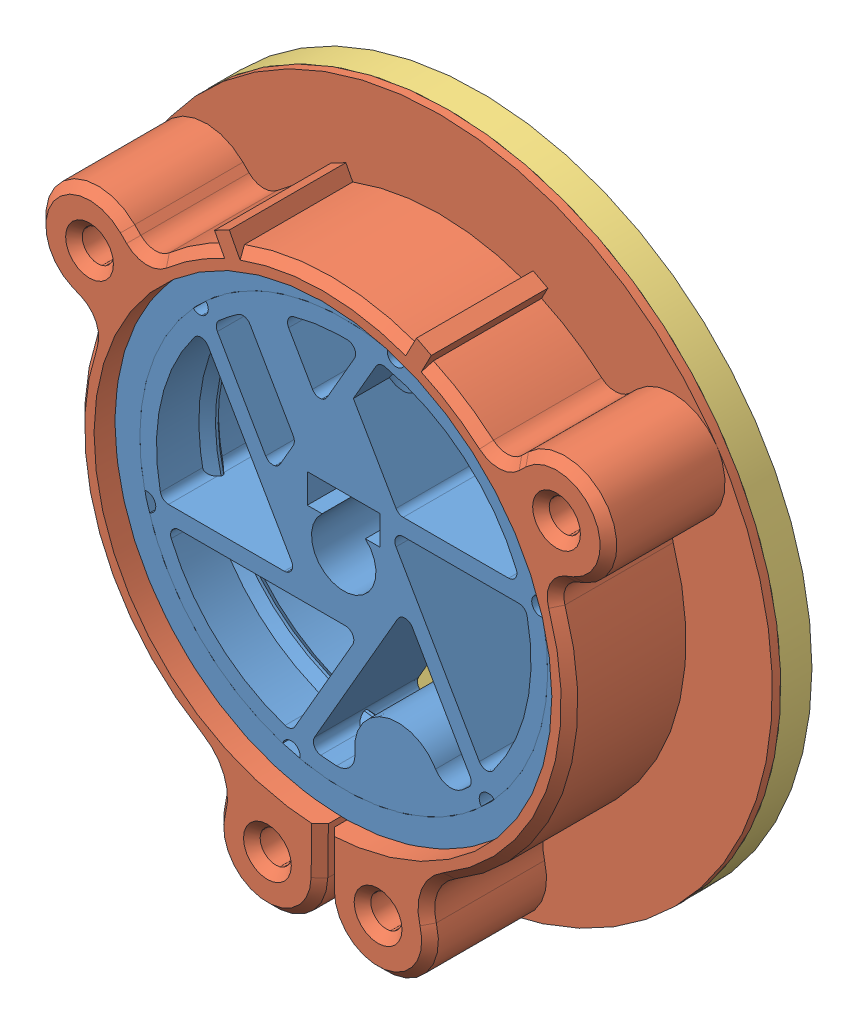
SolidWorks assembly wheel-mold, configuration Default. Lengths in mm.
Overall size (64 64 15).
3 component instances, 3 part files, 3 mates.
Components (placement in the parent):
- drive-wheel-hub-1: drive-wheel-hub [Default] at origin size (44 44 10)
- mold-rim^wheel-mold-1: mold-rim^wheel-mold [Default] at origin size (64 63.47 12.02) (virtual)
- mold-base^wheel-mold-1: mold-base^wheel-mold [Default] at origin size (64 64 3) (virtual)
Mates (geometry in assembly coordinates):
- Coincident1: coordinate: point of drive-wheel-hub-1
- Coincident2: coordinate: unknown of mold-rim^wheel-mold-1
- Coincident3: coordinate: unknown of mold-base^Assem2-1
